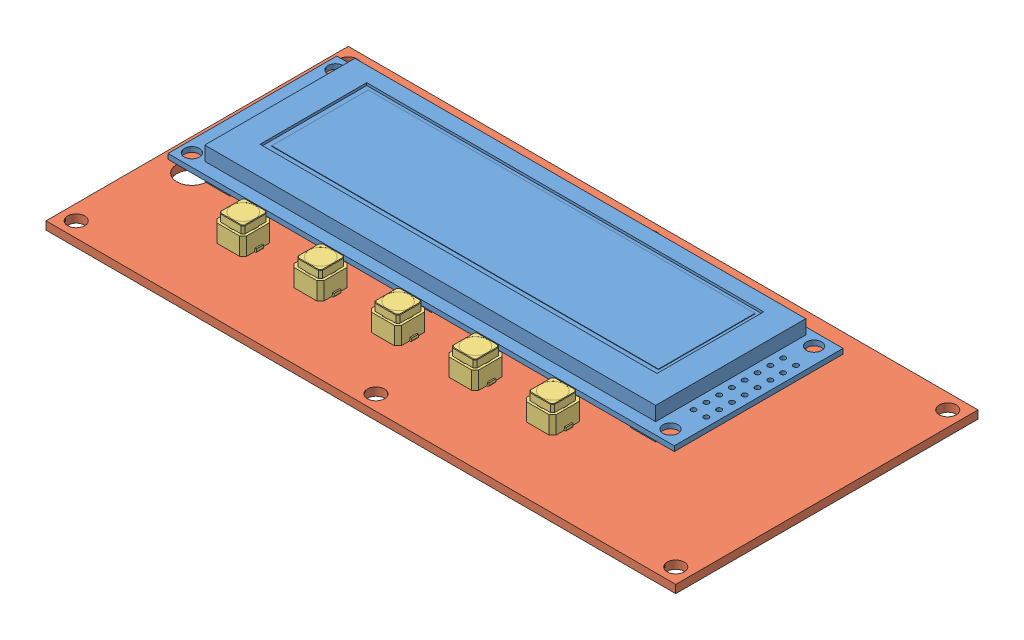
SolidWorks assembly front_panel_assy, configuration Default. Lengths in mm.
Overall size (125 7.9 60).
8 component instances, 4 part files, 22 mates.
Components (placement in the parent):
- front_3mm-1: front_3mm [Default] at (-75.2377 22.9171 25.8875) size (191 4.55 70) (hidden)
- display-2: display [Default] at (-2.2954 20.3671 9.8025) size (100.5 6.3 33.5)
- PCB_sworks-1: PCB_sworks [Default] at (-95.1947 16.2671 23.6389) x (1 0 0) z (0 1 0) size (125 60 1.6)
- alps_SKPMAME010-1: alps_SKPMAME010 [Default] at (-61.5937 17.8671 33.2189) size (6.7 5 6)
- alps_SKPMAME010-16: alps_SKPMAME010 [Default] at (-76.9537 17.8671 33.2189) size (6.7 5 6)
- alps_SKPMAME010-17: alps_SKPMAME010 [Default] at (-92.3137 17.8671 33.2189) size (6.7 5 6)
- alps_SKPMAME010-18: alps_SKPMAME010 [Default] at (-107.6737 17.8671 33.2189) size (6.7 5 6)
- alps_SKPMAME010-19: alps_SKPMAME010 [Default] at (-123.0337 17.8671 33.2189) size (6.7 5 6)
Mates (geometry in assembly coordinates):
- Coincident2: coincident anti-aligned: plane of front_3mm-1 through (-149.1754 25.9171 12.6505) normal (0 0 -1); plane of PCB-1 through (-123.7946 60.1075 12.6505) normal (0 0 1)
- Coincident3: coincident anti-aligned: plane of front_3mm-1 through (-99.1754 25.9171 -5.3495) normal (-1 0 0); plane of PCB-1 through (-99.1754 60.1075 -4.8496) normal (1 0 0)
- Coincident4: coincident aligned: plane of front_3mm-1 through (-75.2377 25.9171 25.8875) normal (0 1 0); plane of PCB-1 through (-145.8385 25.9171 48.8584) normal (0 1 0)
- Distance2: distance = 1.25 mm anti-aligned: plane of front_3mm-1 through (-75.2377 22.9171 25.8875) normal (0 -1 0); plane of display-2 through (-2.2954 24.1671 9.8025) normal (0 1 0)
- Coincident12: coincident anti-aligned: plane of display-2 through (-2.2954 17.8671 9.8025) normal (0 -1 0); plane of PCB_sworks-1 through (-95.1947 17.8671 23.6389) normal (0 1 0)
- Distance5: distance = 2.5 mm aligned: plane of front_3mm-1 through (-205.1976 229.3403 -12.8495) normal (0 0 -1); plane of PCB_sworks-1 through (-146.6976 17.8671 -10.3495) normal (0 0 -1)
- Distance6: distance = 2.5 mm aligned: plane of front_3mm-1 through (-19.1976 229.3403 -12.8495) normal (1 0 0); plane of PCB_sworks-1 through (-21.6976 17.8671 -10.3495) normal (1 0 0)
- Concentric1: concentric anti-aligned: circle of alps_SKPMAME010-1; circle of front_3mm-1
- Parallel1: parallel aligned: plane of front_3mm-1 through (-19.1976 229.3403 52.1505) normal (0 0 1); plane of alps_SKPMAME010-1 through (-64.4483 21.3671 36.5466) normal (0 0 1)
- Coincident16: coincident anti-aligned: plane of PCB_sworks-1 through (-95.1947 17.8671 23.6389) normal (0 1 0); plane of alps_SKPMAME010-1 through (-61.5937 17.8671 33.2189) normal (0 -1 0)
- Parallel14: parallel aligned: plane of front_3mm-1 through (-19.1976 229.3403 52.1505) normal (0 0 1); plane of alps_SKPMAME010-16 through (-79.8083 21.3671 36.5466) normal (0 0 1)
- Coincident17: coincident anti-aligned: plane of PCB_sworks-1 through (-95.1947 17.8671 23.6389) normal (0 1 0); plane of alps_SKPMAME010-16 through (-76.9537 17.8671 33.2189) normal (0 -1 0)
- Concentric12: concentric anti-aligned: circle of front_3mm-1; circle of alps_SKPMAME010-16
- Parallel15: parallel aligned: plane of front_3mm-1 through (-19.1976 229.3403 52.1505) normal (0 0 1); plane of alps_SKPMAME010-17 through (-95.1683 21.3671 36.5466) normal (0 0 1)
- Coincident18: coincident anti-aligned: plane of PCB_sworks-1 through (-95.1947 17.8671 23.6389) normal (0 1 0); plane of alps_SKPMAME010-17 through (-92.3137 17.8671 33.2189) normal (0 -1 0)
- Concentric13: concentric anti-aligned: circle of front_3mm-1; circle of alps_SKPMAME010-17
- Parallel16: parallel aligned: plane of front_3mm-1 through (-19.1976 229.3403 52.1505) normal (0 0 1); plane of alps_SKPMAME010-18 through (-110.5283 21.3671 36.5466) normal (0 0 1)
- Coincident19: coincident anti-aligned: plane of PCB_sworks-1 through (-95.1947 17.8671 23.6389) normal (0 1 0); plane of alps_SKPMAME010-18 through (-107.6737 17.8671 33.2189) normal (0 -1 0)
- Concentric14: concentric anti-aligned: circle of front_3mm-1; circle of alps_SKPMAME010-18
- Parallel17: parallel aligned: plane of front_3mm-1 through (-19.1976 229.3403 52.1505) normal (0 0 1); plane of alps_SKPMAME010-19 through (-125.8883 21.3671 36.5466) normal (0 0 1)
- Coincident20: coincident anti-aligned: plane of PCB_sworks-1 through (-95.1947 17.8671 23.6389) normal (0 1 0); plane of alps_SKPMAME010-19 through (-123.0337 17.8671 33.2189) normal (0 -1 0)
- Concentric15: concentric anti-aligned: circle of front_3mm-1; circle of alps_SKPMAME010-19
